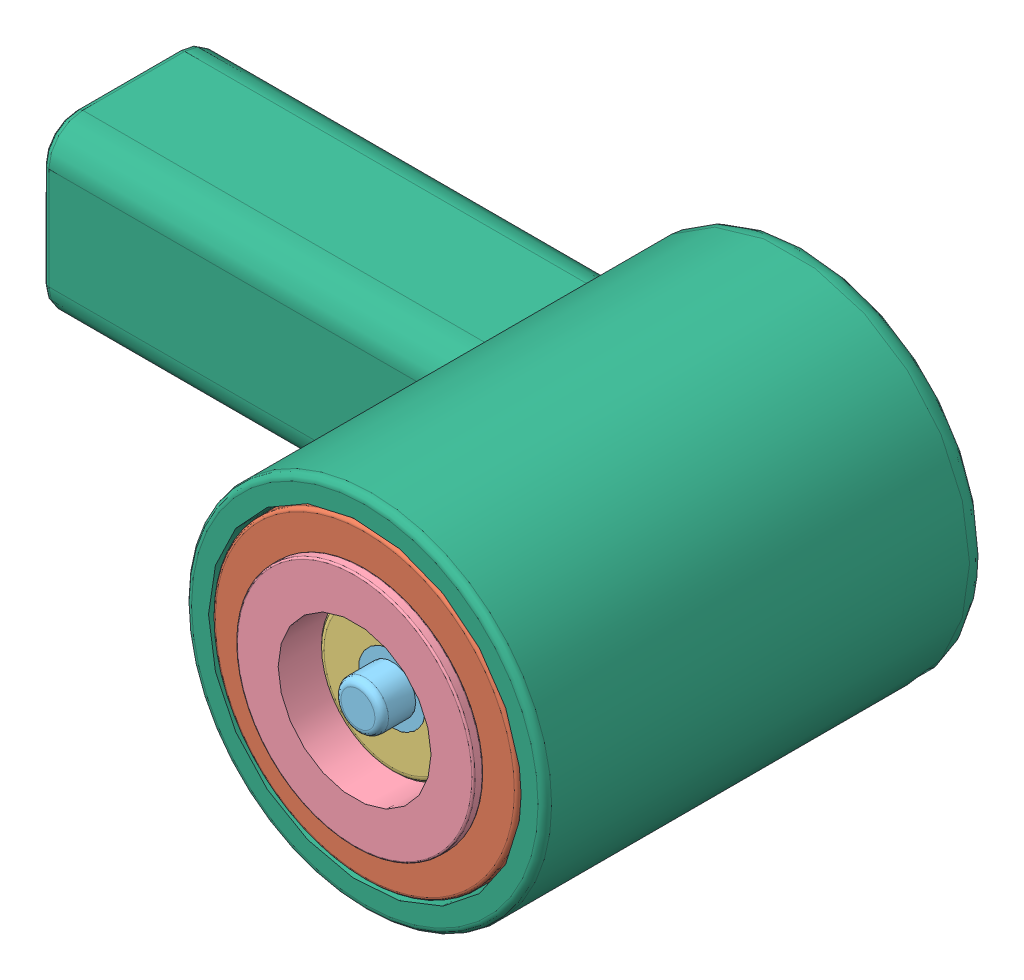
SolidWorks assembly 装配体1, configuration Default. Lengths in mm.
Overall size (22.43 10.89 13.82).
6 component instances, 6 part files, 11 mates.
Components (placement in the parent):
- pcb_公座_无灯-1: pcb_公座_无灯 [Default] at (23.4613 12.2398 -14.6095) x (0.001644 -0.999999 0) z (0 0 -1) size (7.8 7.8 0.9)
- 磁铁_公座-1: 磁铁_公座 [Default] at (23.4613 12.2398 -13.8095) size (9 9 4)
- 胶件_公座-1: 胶件_公座 [Default] at (23.4613 12.2398 -13.8095) size (7.8 7.8 4)
- 铜套_公座-镀金-1: 铜套_公座-镀金 [Default] at (23.4613 12.2398 -9.8095) x (0.999999 0.001644 0) z (0 0 1) size (7 7 6.8)
- 铜针_公座-1: 铜针_公座 [Default] at (23.4613 12.2398 -14.5095) size (2.3 2.3 6.2)
- 充电线_磁吸头_外壳-1: 充电线_磁吸头_外壳 [Default] at (23.4613 12.2398 -23.3095) size (22.43 10.89 13.52)
Mates (geometry in assembly coordinates):
- 同心1: concentric aligned: cylinder of 磁铁_公座-1 through (23.4613 12.2398 12.4575) axis (0 0 -1) radius 2.85; cylinder of 胶件_公座-1 through (23.4613 12.2398 11.6575) axis (0 0 -1) radius 2.2
- 同心2: concentric aligned: cylinder of 胶件_公座-1 through (23.4613 12.2398 11.6575) axis (0 0 -1) radius 2.2; cylinder of 铜套_公座-镀金-1 through (23.4613 12.2398 12.7575) axis (0 0 -1) radius 2.25
- 同心4: concentric aligned: cylinder of 磁铁_公座-1 through (23.4613 12.2398 12.4575) axis (0 0 -1) radius 2.85; cylinder of 铜针_公座-1 through (23.4613 12.2398 11.6575) axis (0 0 -1) radius 1
- 重合1: coincident anti-aligned: plane of 胶件_公座-1 through (23.4613 12.2398 8.1575) normal (0 0 -1); plane of 铜针_公座-1 through (23.4613 12.2398 8.1575) normal (0 0 1)
- 重合2: coincident anti-aligned: plane of 磁铁_公座-1 through (23.4613 12.2398 12.4575) normal (0 0 1); plane of 铜套_公座-镀金-1 through (23.4613 12.2398 12.4575) normal (0 0 -1)
- 重合3: coincident anti-aligned: plane of 磁铁_公座-1 through (23.4613 12.2398 8.4575) normal (0 0 -1); plane of 胶件_公座-1 through (23.4613 12.2398 8.4575) normal (0 0 1)
- 同心5: concentric anti-aligned: cylinder of pcb_公座_无灯-1 through (23.4613 12.2398 6.8575) axis (0 0 1) radius 3.9; cylinder of 磁铁_公座-1 through (23.4613 12.2398 12.4575) axis (0 0 -1) radius 4.5
- 重合4: coincident anti-aligned: plane of pcb_公座_无灯-1 through (23.4613 12.2398 7.6575) normal (0 0 1); plane of 胶件_公座-1 through (23.4613 12.2398 7.6575) normal (0 0 -1)
- 平行1: parallel anti-aligned: plane of pcb_公座_无灯-1 through (22.6573 14.6434 6.8575) normal (0.999999 0.001644 0); plane of 铜套_公座-镀金-1 through (22.8113 12.2387 8.6575) normal (-0.999999 -0.001644 0)
- 同心6: concentric aligned: cylinder of 磁铁_公座-1 through (23.4613 12.2398 -9.8095) axis (0 0 -1) radius 4.5; cylinder of 充电线_磁吸头_外壳-1 through (23.4613 12.2398 -9.8095) axis (0 0 -1) radius 4.6
- 重合6: coincident anti-aligned: plane of 磁铁_公座-1 through (23.4613 12.2398 -13.8095) normal (0 0 -1); plane of 充电线_磁吸头_外壳-1 through (23.4613 12.2398 -13.8095) normal (0 0 1)
